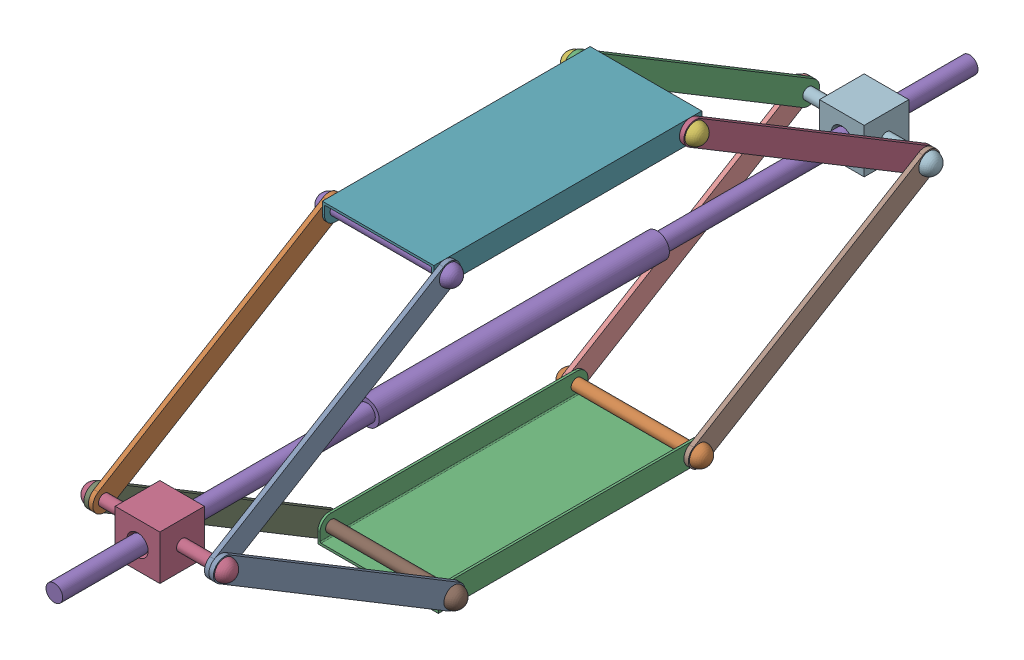
SolidWorks assembly 03_CSWA_ScissorLift, configuration Default. Lengths in mm.
Overall size (85.09 174.86 520.7).
17 component instances, 7 part files, 30 mates.
Components (placement in the parent):
- 03_CSWA_Link-1: 03_CSWA_Link [Default] at (-14.6084 82.4459 4.2944) x (0 0.516498 0.856288) z (0 -0.856288 0.516498) size (165.1 2.54 12.7)
- 03_CSWA_LongPin-1: 03_CSWA_LongPin [Default] at (-51.4384 43.0887 -200.6548) size (85.09 11.43 11.43)
- 03_CSWA_LowerBase-1: 03_CSWA_LowerBase [Default] at (-51.4384 43.0887 -54.6048) x (-1 0 0) z (0 0 -1) size (68.58 12.7 152.4)
- 03_CSWA_Pivot-1: 03_CSWA_Pivot [Default] at (-51.4384 121.8031 56.8435) x (1 0 0) z (0 -1 0) size (85.09 25.4 25.4)
- 03_CSWA_Shaft-1: 03_CSWA_Shaft [Default] at (-51.4384 121.8031 -130.8048) x (0 0 -1) z (-0.542598 0.839992 0) size (520.7 13.97 13.97)
- 03_CSWA_ShortPin-1: 03_CSWA_ShortPin [Default] at (-51.4384 200.5174 -200.6548) size (80.01 11.43 11.43)
- 03_CSWA_UpperBase-1: 03_CSWA_UpperBase [Default] at (-51.4384 200.5174 -207.0048) x (-1 0 0) z (0 0 1) size (63.5 12.7 152.4)
- 03_CSWA_Link-2: 03_CSWA_Link [Default] at (-14.6084 82.4459 -265.9039) x (0 -0.516498 0.856288) z (0 -0.856288 -0.516498) size (165.1 2.54 12.7)
- 03_CSWA_Link-3: 03_CSWA_Link [Default] at (-88.2684 82.4459 4.2944) x (0 -0.516498 -0.856288) z (0 -0.856288 0.516498) size (165.1 2.54 12.7)
- 03_CSWA_Link-4: 03_CSWA_Link [Default] at (-88.2684 82.4459 -265.9039) x (0 -0.516498 0.856288) z (0 0.856288 0.516498) size (165.1 2.54 12.7)
- 03_CSWA_LongPin-2: 03_CSWA_LongPin [Default] at (-51.4384 43.0887 -60.9548) size (85.09 11.43 11.43)
- 03_CSWA_Pivot-2: 03_CSWA_Pivot [Default] at (-51.4384 121.8031 -343.8531) x (1 0 0) z (0 -1 0) size (85.09 25.4 25.4)
- 03_CSWA_Link-5: 03_CSWA_Link [Default] at (-17.1484 161.1602 4.2944) x (0 -0.516498 0.856288) z (0 -0.856288 -0.516498) size (165.1 2.54 12.7)
- 03_CSWA_Link-6: 03_CSWA_Link [Default] at (-83.1884 161.1602 4.2944) x (0 -0.516498 0.856288) z (0 -0.856288 -0.516498) size (165.1 2.54 12.7)
- 03_CSWA_Link-7: 03_CSWA_Link [Default] at (-85.7284 161.1602 -265.9039) x (0 0.516498 0.856288) z (0 0.856288 -0.516498) size (165.1 2.54 12.7)
- 03_CSWA_Link-8: 03_CSWA_Link [Default] at (-17.1484 161.1602 -265.9039) x (0 0.516498 0.856288) z (0 -0.856288 0.516498) size (165.1 2.54 12.7)
- 03_CSWA_ShortPin-2: 03_CSWA_ShortPin [Default] at (-51.4384 200.5174 -60.9548) size (80.01 11.43 11.43)
Mates (geometry in assembly coordinates):
- Coincident1: coincident anti-aligned: circle of 03_CSWA_LowerBase-1; circle of 03_CSWA_Link-4
- Coincident2: coincident anti-aligned: circle of 03_CSWA_LowerBase-1; circle of 03_CSWA_Link-3
- Coincident3: coincident aligned: circle of 03_CSWA_LowerBase-1; circle of 03_CSWA_Link-2
- Coincident4: coincident aligned: circle of 03_CSWA_Link-1; circle of 03_CSWA_LowerBase-1
- Parallel2: parallel anti-aligned: plane of 03_CSWA_LowerBase-1 through (-51.4384 36.7387 -207.0048) normal (0 -1 0)
- Parallel1: parallel aligned: plane of 03_CSWA_LowerBase-1 through (-17.1484 43.0887 -207.0048) normal (1 0 0)
- Concentric1: concentric anti-aligned: cylinder of 03_CSWA_Link-1 through (-17.1484 43.0887 -60.9548) axis (1 0 0) radius 3.175; cylinder of 03_CSWA_LongPin-2 through (-88.2684 43.0887 -60.9548) axis (-1 0 0) radius 3.175
- Coincident7: coincident anti-aligned: plane of 03_CSWA_Link-1 through (-14.6084 43.0887 -60.9548) normal (1 0 0); plane of 03_CSWA_LongPin-2 through (-14.6084 43.0887 -60.9548) normal (-1 0 0)
- Coincident8: coincident anti-aligned: circle of 03_CSWA_LongPin-1; circle of 03_CSWA_Link-4
- Parallel3: parallel anti-aligned: plane of 03_CSWA_LowerBase-1 through (-51.4384 38.0087 -207.0048) normal (0 1 0); plane of 03_CSWA_Pivot-1 through (-64.1384 109.1031 82.2435) normal (0 -1 0)
- Coincident11: coincident anti-aligned: circle of 03_CSWA_Pivot-1; circle of 03_CSWA_Link-3
- Coincident12: coincident aligned: circle of 03_CSWA_Link-1; circle of 03_CSWA_Pivot-1
- Parallel4: parallel anti-aligned: plane of 03_CSWA_LowerBase-1 through (-51.4384 38.0087 -207.0048) normal (0 1 0); plane of 03_CSWA_Pivot-2 through (-64.1384 109.1031 -318.4531) normal (0 -1 0)
- Coincident14: coincident anti-aligned: circle of 03_CSWA_Link-4; circle of 03_CSWA_Pivot-2
- Concentric2: concentric anti-aligned: cylinder of 03_CSWA_Link-2 through (-17.1484 121.8031 -331.1531) axis (1 0 0) radius 3.175; cylinder of 03_CSWA_Pivot-2 through (-93.9834 121.8031 -331.1531) axis (-1 0 0) radius 3.175
- Concentric4: concentric anti-aligned: cylinder of 03_CSWA_Pivot-1 through (-93.9834 121.8031 69.5435) axis (-1 0 0) radius 3.175; cylinder of 03_CSWA_Link-5 through (-19.6884 121.8031 69.5435) axis (1 0 0) radius 3.175
- Coincident17: coincident anti-aligned: plane of 03_CSWA_Link-1 through (-17.1484 43.0887 -60.9548) normal (-1 0 0); plane of 03_CSWA_Link-5 through (-17.1484 200.5174 -60.9548) normal (1 0 0)
- Coincident18: coincident anti-aligned: circle of 03_CSWA_Link-3; circle of 03_CSWA_Link-6
- Coincident19: coincident aligned: circle of 03_CSWA_Link-4; circle of 03_CSWA_Link-7
- Coincident20: coincident aligned: circle of 03_CSWA_Link-2; circle of 03_CSWA_Link-8
- Parallel6: parallel aligned: plane of 03_CSWA_LowerBase-1 through (-51.4384 38.0087 -207.0048) normal (0 1 0); plane of 03_CSWA_UpperBase-1 through (-51.4384 206.8674 -54.6048) normal (0 1 0)
- Coincident22: coincident aligned: circle of 03_CSWA_UpperBase-1; circle of 03_CSWA_Link-6
- Coincident23: coincident aligned: circle of 03_CSWA_UpperBase-1; circle of 03_CSWA_Link-5
- Coincident24: coincident aligned: circle of 03_CSWA_UpperBase-1; circle of 03_CSWA_Link-8
- Coincident25: coincident anti-aligned: circle of 03_CSWA_UpperBase-1; circle of 03_CSWA_Link-7
- Coincident26: coincident aligned: circle of 03_CSWA_Pivot-1; cylinder of 03_CSWA_Shaft-1 through (-51.4384 121.8031 129.5452) axis (0 0 1) radius 4.7625
- Concentric5: concentric anti-aligned: cylinder of 03_CSWA_Shaft-1 through (-51.4384 121.8031 129.5452) axis (0 0 1) radius 4.7625; cylinder of 03_CSWA_Pivot-2 through (-51.4384 121.8031 -318.4531) axis (0 0 -1) radius 4.7625
- Coincident29: coincident aligned: circle of 03_CSWA_Link-5; circle of 03_CSWA_ShortPin-2
- Coincident30: coincident aligned: circle of 03_CSWA_ShortPin-1; circle of 03_CSWA_Link-8
- Width1: width aligned: plane of 03_CSWA_LowerBase-1 through (-51.4384 43.0887 -54.6048) normal (0 0 1); plane of 03_CSWA_LowerBase-1 through (-51.4384 43.0887 -207.0048) normal (0 0 -1); plane of 03_CSWA_Shaft-1 through (-51.4384 121.8031 129.5452) normal (0 0 1); plane of 03_CSWA_Shaft-1 through (-51.4384 121.8031 -391.1548) normal (0 0 -1)
